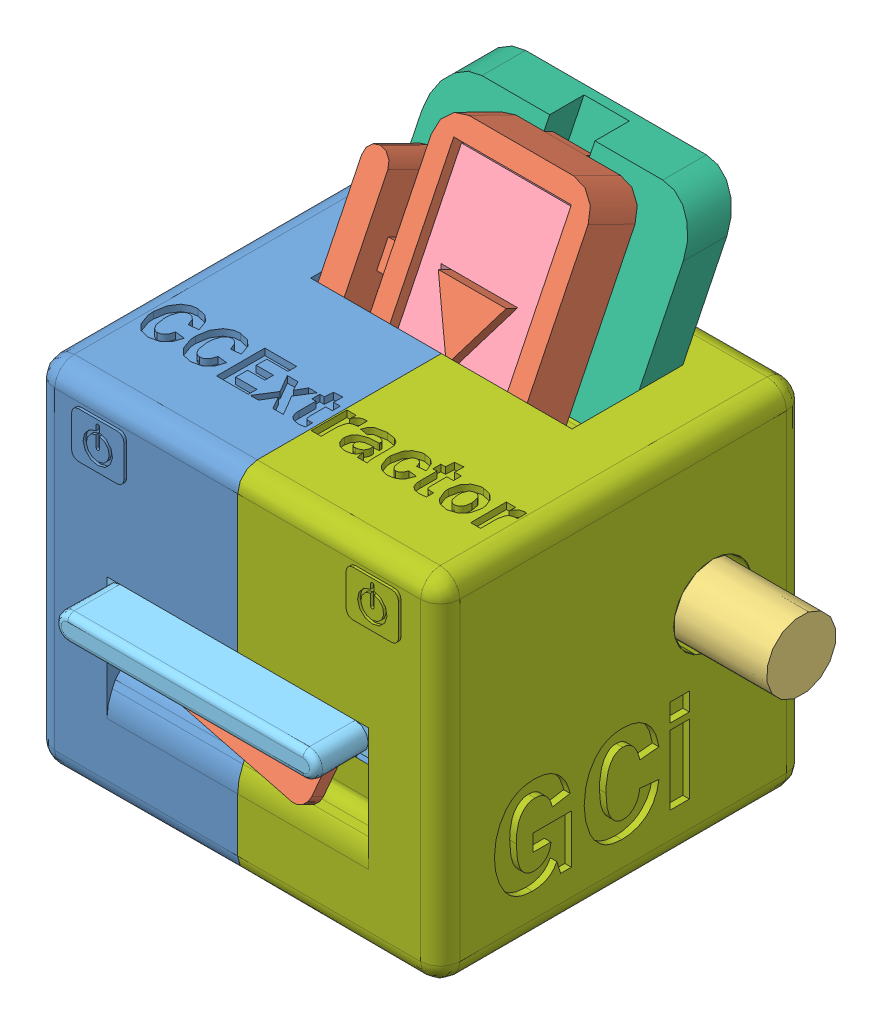
SolidWorks assembly [A] Functional-Multi Color Swap Filament, configuration Default. Lengths in mm.
Overall size (479.65 519.15 418.41).
7 component instances, 7 part files, 17 mates.
Components (placement in the parent):
- [P] Functional-Multi Color Swap Filament - Main Body Left-1: [P] Functional-Multi Color Swap Filament - Main Body Left [Default] at (293.0443 -24.6756 171.0885) size (196.85 342.9 358.14)
- [P] Functional-Multi Color Swap Filament - TV and Script-1: [P] Functional-Multi Color Swap Filament - TV and Script [Default] at (250.7672 257.4299 333.5459) x (0 -0.897542 0.440929) z (-1 0 0) size (467.82 164.89 217.08)
- [P] Functional-Multi Color Swap Filament - Turner-1: [P] Functional-Multi Color Swap Filament - Turner [Default] at (311.0443 172.1939 261.8246) x (-1 0 0) z (0 -0.977711 0.209954) size (304.8 103.43 108)
- [P] Functional-Multi Color Swap Filament - TV Background-1: [P] Functional-Multi Color Swap Filament - TV Background [Default] at (295.5843 328.9681 281.212) x (0 -0.897542 0.440929) z (-1 0 0) size (209.55 25.4 107.95)
- [P] Functional-Multi Color Swap Filament - Bill-1: [P] Functional-Multi Color Swap Filament - Bill [Default] at (293.0443 -24.6756 171.0885) size (304.8 88.9 90.8)
- [P] Functional-Multi Color Swap Filament - Tray-1: [P] Functional-Multi Color Swap Filament - Tray [Default] at (293.0443 -25.337 169.7421) size (304.8 180.81 123.02)
- [P] Functional-Multi Color Swap Filament - Main Body Right-1: [P] Functional-Multi Color Swap Filament - Main Body Right [Default] at (287.9643 -24.6756 171.0885) size (245.11 342.9 358.14)
Mates (geometry in assembly coordinates):
- Coincident1: coincident anti-aligned: plane of [P] Functional-Multi Color Swap Filament - Main Body Left-1 through (420.0443 318.2244 265.2653) normal (0 0.440929 0.897542); plane of [P] Functional-Multi Color Swap Filament - TV and Script-1 through (181.2843 320.5684 264.1138) normal (0 -0.440929 -0.897542)
- Distance1: distance = 2.54 mm anti-aligned: plane of [P] Functional-Multi Color Swap Filament - TV and Script-1 through (168.5843 342.9676 309.7089) normal (-1 0 0); plane of [P] Functional-Multi Color Swap Filament - Main Body Left-1 through (166.0443 292.8244 328.7653) normal (1 0 0)
- Coincident9: coincident anti-aligned: plane of [P] Functional-Multi Color Swap Filament - Main Body Left-1 through (271.0443 448.796 167.6958) normal (1 0 0); plane of [P] Functional-Multi Color Swap Filament - Turner-1 through (271.0443 172.1939 261.8246) normal (-1 0 0)
- RackPinionMate1: rack pinion = 76.2 mm: line of [P] Functional-Multi Color Swap Filament - TV and Script-1 through (313.0443 178.031 301.8266) axis (0 0.897542 -0.440929); circle of [P] Functional-Multi Color Swap Filament - Turner-1
- Width1: width anti-aligned: plane of [P] Functional-Multi Color Swap Filament - TV Background-1 through (349.5593 246.1277 350.2078) normal (1 0 0); plane of [P] Functional-Multi Color Swap Filament - TV Background-1 through (241.6093 434.2077 257.8112) normal (-1 0 0); plane of [P] Functional-Multi Color Swap Filament - TV and Script-1 through (352.7343 437.0574 256.4113) normal (-1 0 0); plane of [P] Functional-Multi Color Swap Filament - TV and Script-1 through (238.4343 437.0574 256.4113) normal (1 0 0)
- Width2: width anti-aligned: plane of [P] Functional-Multi Color Swap Filament - TV Background-1 through (241.6093 246.1277 350.2078) normal (0 -0.897542 0.440929); plane of [P] Functional-Multi Color Swap Filament - TV Background-1 through (349.5593 434.2077 257.8112) normal (0 0.897542 -0.440929); plane of [P] Functional-Multi Color Swap Filament - TV and Script-1 through (238.4343 243.278 351.6078) normal (0 0.897542 -0.440929); plane of [P] Functional-Multi Color Swap Filament - TV and Script-1 through (238.4343 437.0574 256.4113) normal (0 -0.897542 0.440929)
- Coincident17: coincident anti-aligned: plane of [P] Functional-Multi Color Swap Filament - TV and Script-1 through (250.7672 250.627 319.698) normal (0 0.440929 0.897542); plane of [P] Functional-Multi Color Swap Filament - TV Background-1 through (295.5843 328.9681 281.212) normal (0 -0.440929 -0.897542)
- Concentric1: concentric aligned: cylinder of [P] Functional-Multi Color Swap Filament - Main Body Left-1 through (91.4392 172.1939 261.8246) axis (1 0 0) radius 63.5; cylinder of [P] Functional-Multi Color Swap Filament - Turner-1 through (271.0443 172.1939 261.8246) axis (1 0 0) radius 33.749
- Coincident18: coincident anti-aligned: plane of [P] Functional-Multi Color Swap Filament - Main Body Left-1 through (38.9701 229.3244 511.6885) normal (0 0 -1); plane of [P] Functional-Multi Color Swap Filament - Bill-1 through (96.1943 165.8244 511.6885) normal (0 0 1)
- Coincident19: coincident anti-aligned: plane of [P] Functional-Multi Color Swap Filament - Main Body Left-1 through (38.9701 229.3244 486.6885) normal (0 -1 0); plane of [P] Functional-Multi Color Swap Filament - Bill-1 through (96.1943 229.3244 511.6885) normal (0 1 0)
- Coincident20: coincident anti-aligned: plane of [P] Functional-Multi Color Swap Filament - Main Body Left-1 through (140.6443 -24.6756 171.0885) normal (1 0 0); plane of [P] Functional-Multi Color Swap Filament - Bill-1 through (140.6443 -24.6756 171.0885) normal (-1 0 0)
- Coincident21: coincident anti-aligned: plane of [P] Functional-Multi Color Swap Filament - Main Body Left-1 through (104.7518 263.7554 247.9034) normal (0 0.440929 0.897542); plane of [P] Functional-Multi Color Swap Filament - Tray-1 through (420.0443 317.563 221.4697) normal (0 -0.440929 -0.897542)
- Coincident22: coincident anti-aligned: plane of [P] Functional-Multi Color Swap Filament - Main Body Left-1 through (-52.646 267.9883 256.5198) normal (0 0.897542 -0.440929); plane of [P] Functional-Multi Color Swap Filament - Tray-1 through (96.1943 267.3269 255.1735) normal (0 -0.897542 0.440929)
- Coincident23: coincident anti-aligned: plane of [P] Functional-Multi Color Swap Filament - Main Body Left-1 through (140.6443 -24.6756 171.0885) normal (1 0 0); plane of [P] Functional-Multi Color Swap Filament - Tray-1 through (140.6443 -25.337 169.7421) normal (-1 0 0)
- Concentric2: concentric aligned: cylinder of [P] Functional-Multi Color Swap Filament - Main Body Left-1 through (239.7043 285.5288 493.9928) axis (1 0 0) radius 25.4; cylinder of [P] Functional-Multi Color Swap Filament - Main Body Right-1 through (244.7843 285.5288 493.9928) axis (1 0 0) radius 25.4
- Concentric3: concentric aligned: cylinder of [P] Functional-Multi Color Swap Filament - Main Body Left-1 through (239.7043 8.02 203.7841) axis (1 0 0) radius 25.4; cylinder of [P] Functional-Multi Color Swap Filament - Main Body Right-1 through (244.7843 8.02 203.7841) axis (1 0 0) radius 25.4
- Coincident24: coincident anti-aligned: plane of [P] Functional-Multi Color Swap Filament - Main Body Left-1 through (293.0443 -24.6756 171.0885) normal (1 0 0); plane of [P] Functional-Multi Color Swap Filament - Main Body Right-1 through (293.0443 -24.6756 171.0885) normal (-1 0 0)
